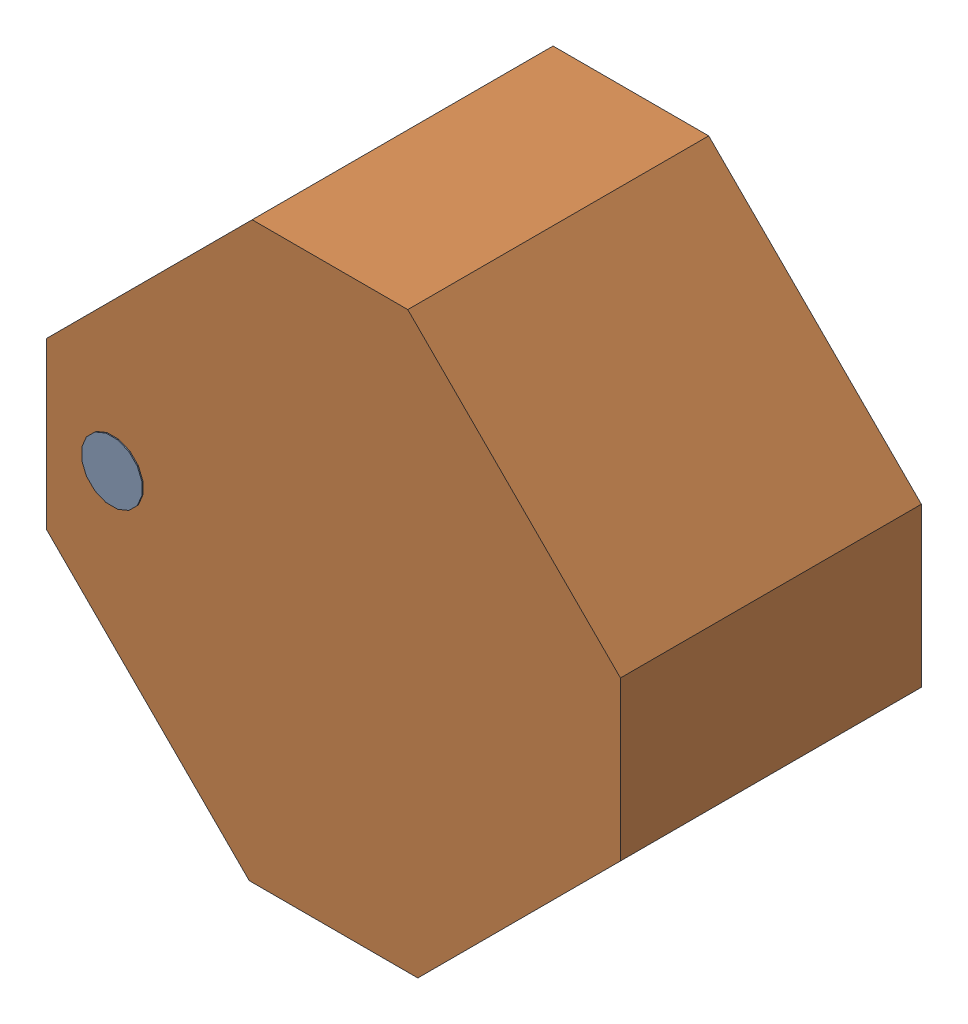
SolidWorks assembly L1, configuration Default. Lengths in mm.
Overall size (5.72 5.72 3.01).
4 component instances, 2 part files, 0 mates.
Components (placement in the parent):
- 6638399408-1: 6638399408 [Default] at (30.566 10.541 2) size (0.6 0.6 1.01)
  - Extruded_23-1: Extruded_23 [Default] at origin size (0.6 0.6 1.01)
- 6638399328-1: 6638399328 [Default] at (32.766 10.541 0) size (5.72 5.72 3)
  - Extruded_24-1: Extruded_24 [Default] at origin size (5.72 5.72 3)
